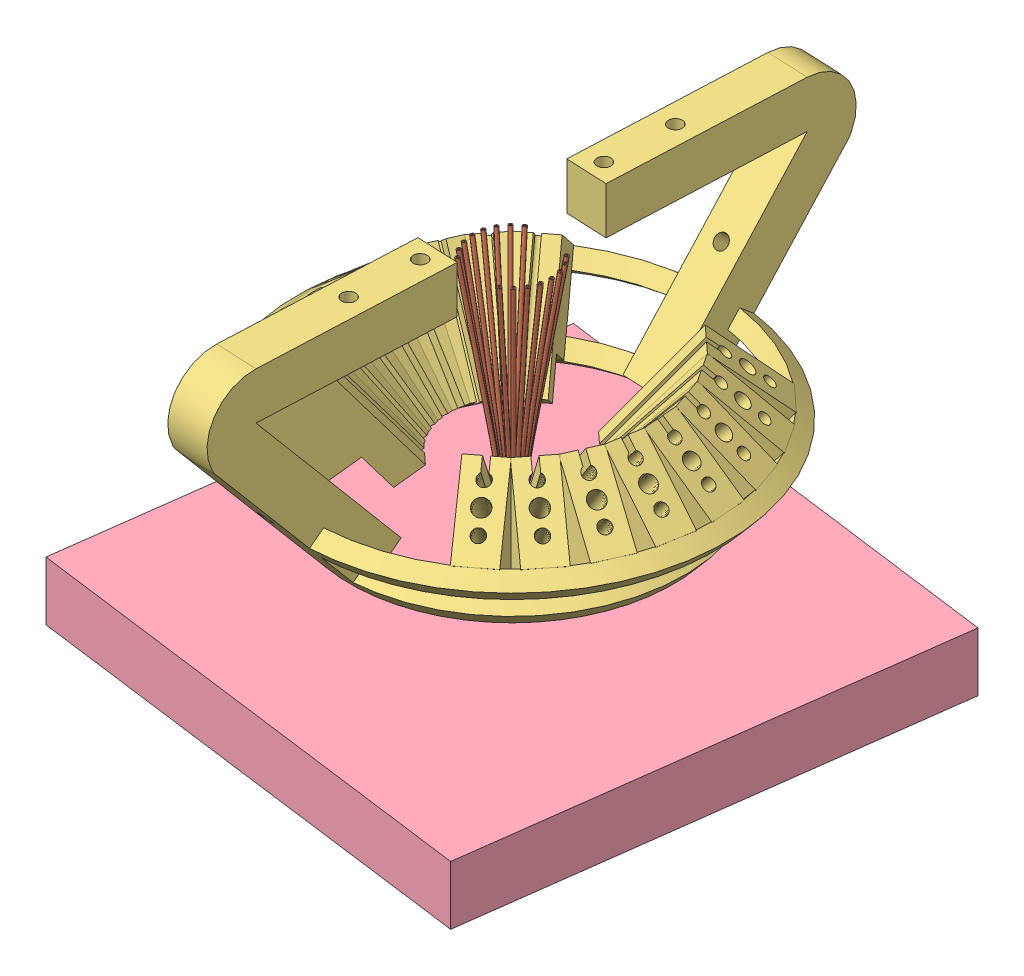
SolidWorks assembly DriveAssembling_Step1, configuration Default. Lengths in mm.
Overall size (60.67 33.72 62.09).
19 component instances, 4 part files, 5 mates.
Components (placement in the parent):
- MainCanula-1: MainCanula [Default] at (0 2 0) size (2.41 8 2.41)
- 30g_slightly_curved-1: 30g_slightly_curved [Default] at (0.4899 12 0.0382) x (0.96591 0 0.25888) z (-0.25888 0 0.96591) size (2.93 29.8 0.32)
- 30g_slightly_curved-2: 30g_slightly_curved [Default] at (0.4831 12 -0.0899) x (1 0 0.000063) z (-0.000063 0 1) size (2.93 29.8 0.32)
- 30g_slightly_curved-3: 30g_slightly_curved [Default] at (0.4434 12 -0.2119) x (0.965942 0 -0.258759) z (0.258759 0 0.965942) size (2.93 29.8 0.32)
- 30g_slightly_curved-4: 30g_slightly_curved [Default] at (0.3734 12 -0.3194) x (0.866057 0 -0.499946) z (0.499946 0 0.866057) size (2.93 29.8 0.32)
- 30g_slightly_curved-5: 30g_slightly_curved [Default] at (0.278 12 -0.4052) x (0.707151 0 -0.707062) z (0.707062 0 0.707151) size (2.93 29.8 0.32)
- 30g_slightly_curved-6: 30g_slightly_curved [Default] at (-0.3194 12 -0.3734) x (-0.499946 0 -0.866057) z (0.866057 0 -0.499946) size (2.93 29.8 0.32)
- 30g_slightly_curved-7: 30g_slightly_curved [Default] at (-0.4052 12 -0.278) x (-0.707062 0 -0.707151) z (0.707151 0 -0.707062) size (2.93 29.8 0.32)
- 30g_slightly_curved-8: 30g_slightly_curved [Default] at (-0.4634 12 -0.1637) x (-0.865994 0 -0.500054) z (0.500054 0 -0.865994) size (2.93 29.8 0.32)
- 30g_slightly_curved-9: 30g_slightly_curved [Default] at (-0.4899 12 -0.0382) x (-0.96591 0 -0.25888) z (0.25888 0 -0.96591) size (2.93 29.8 0.32)
- 30g_slightly_curved-10: 30g_slightly_curved [Default] at (-0.4831 12 0.0899) x (-1 0 -0.000063) z (0.000063 0 -1) size (2.93 29.8 0.32)
- 30g_slightly_curved-11: 30g_slightly_curved [Default] at (-0.4434 12 0.2119) x (-0.965942 0 0.258759) z (-0.258759 0 -0.965942) size (2.93 29.8 0.32)
- 30g_slightly_curved-12: 30g_slightly_curved [Default] at (-0.3734 12 0.3194) x (-0.866057 0 0.499946) z (-0.499946 0 -0.866057) size (2.93 29.8 0.32)
- 30g_slightly_curved-13: 30g_slightly_curved [Default] at (-0.278 12 0.4052) x (-0.707151 0 0.707062) z (-0.707062 0 -0.707151) size (2.93 29.8 0.32)
- 30g_slightly_curved-14: 30g_slightly_curved [Default] at (0.3194 12 0.3734) x (0.499946 0 0.866057) z (-0.866057 0 0.499946) size (2.93 29.8 0.32)
- 30g_slightly_curved-15: 30g_slightly_curved [Default] at (0.4052 12 0.278) x (0.707062 0 0.707151) z (-0.707151 0 0.707062) size (2.93 29.8 0.32)
- 30g_slightly_curved-16: 30g_slightly_curved [Default] at (0.4634 12 0.1637) x (0.865994 0 0.500054) z (-0.500054 0 0.865994) size (2.93 29.8 0.32)
- drive_circle_16-1: drive_circle_16 [Default] at (0 7 0) x (0.608761 0 0.793353) z (-0.793353 0 0.608761) size (47.61 33.72 39.95)
- SingleCanulaBase-1: SingleCanulaBase [Default] x (0.991445 0 0.130526) z (-0.130526 0 0.991445) size (40 5 40)
Mates (geometry in assembly coordinates):
- Coincident1: coincident aligned: plane of MainCanula-1 through (0 0 0) normal (0 -1 0); plane of 30g_slightly_curved-1 through (0.6831 0 0.0899) normal (0 -1 0)
- Concentric2: concentric anti-aligned: circle of 30g_slightly_curved-1; circle of assembly
- Concentric3: concentric aligned: circle of MainCanula-1; circle of SingleCanulaBase-1
- Coincident3: coincident aligned: plane of MainCanula-1 through (0 0 0) normal (0 -1 0); plane of SingleCanulaBase-1 through (0 0 0) normal (0 -1 0)
- Concentric4: concentric anti-aligned: circle of MainCanula-1; circle of drive_circle_16-1
